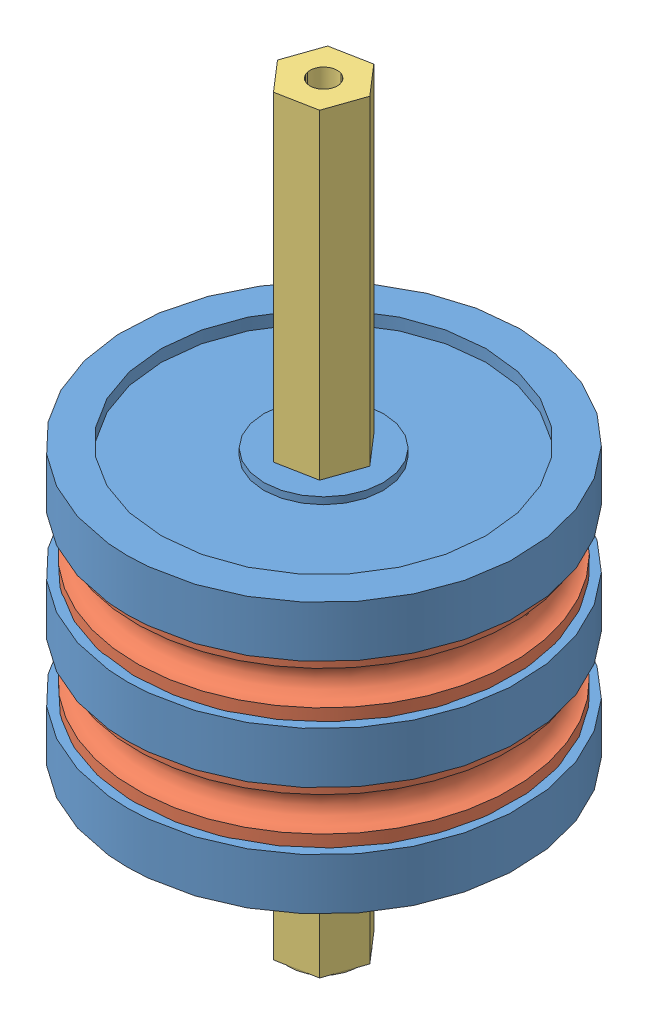
SolidWorks assembly Wheel_Assem, configuration Default. Lengths in mm.
Overall size (100.46 139.95 100.46).
6 component instances, 3 part files, 14 mates.
Components (placement in the parent):
- Wheel-1: Wheel [Default] at origin size (73.03 9.53 73.03)
- Hex_Spacer-1: Hex_Spacer [Default] at (0 8.5725 0) x (0.982054 0 -0.188601) z (0.188601 0 0.982054) size (71.22 12.7 71.22)
- Wheel-2: Wheel [Default] at (0 20.32 0) size (73.03 9.53 73.03)
- Hex_Spacer-2: Hex_Spacer [Default] at (0 28.8925 0) x (0.65436 0 0.756183) z (-0.756183 0 0.65436) size (71.22 12.7 71.22)
- Wheel-3: Wheel [Default] at (0 40.64 0) size (73.03 9.53 73.03)
- Hex_Shaft-1: Hex_Shaft [Default] at (0 -30.9284 0) x (0.982054 0 -0.188601) z (0.188601 0 0.982054) size (14.66 139.95 12.7)
Mates (geometry in assembly coordinates):
- Concentric1: concentric aligned: circle of Wheel-1; circle of Hex_Spacer-1
- Coincident1: coincident anti-aligned: plane of Wheel-1 through (0 8.5725 0) normal (0 1 0); plane of Hex_Spacer-1 through (0 8.5725 0) normal (0 -1 0)
- Parallel1: parallel aligned: plane of Wheel-1 through (2.4028 2.2225 -6.9275) normal (0.188601 0 0.982054); plane of Hex_Spacer-1 through (2.571 21.2725 -7.4124) normal (0.188601 0 0.982054)
- Coincident3: coincident anti-aligned: plane of Hex_Spacer-1 through (0 21.2725 0) normal (0 1 0); plane of Wheel-2 through (0 21.2725 0) normal (0 -1 0)
- Coincident5: coincident aligned: plane of Wheel-1 through (7.2008 2.2225 -1.3829) normal (-0.756183 0 0.65436); plane of Wheel-2 through (7.2008 22.5425 -1.3829) normal (-0.756183 0 0.65436)
- Coincident6: coincident anti-aligned: plane of Wheel-2 through (0 28.8925 0) normal (0 1 0); plane of Hex_Spacer-2 through (0 28.8925 0) normal (0 -1 0)
- Concentric3: concentric aligned: circle of Wheel-2; circle of Hex_Spacer-2
- Parallel2: parallel aligned: plane of Wheel-1 through (-4.798 2.2225 -5.5446) normal (0.944784 0 0.327694); plane of Hex_Spacer-2 through (-5.1339 41.5925 -5.9327) normal (0.944784 0 0.327694)
- Concentric4: concentric aligned: circle of Wheel-1; circle of Wheel-2
- Coincident8: coincident anti-aligned: plane of Hex_Spacer-2 through (0 41.5925 0) normal (0 1 0); plane of Wheel-3 through (0 41.5925 0) normal (0 -1 0)
- Concentric5: concentric aligned: circle of Wheel-1; circle of Wheel-3
- Coincident9: coincident aligned: plane of Wheel-1 through (-4.798 2.2225 -5.5446) normal (0.944784 0 0.327694); plane of Wheel-3 through (-4.798 42.8625 -5.5446) normal (0.944784 0 0.327694)
- Concentric6: concentric anti-aligned: circle of Wheel-3; circle of Hex_Shaft-1
- Coincident10: coincident: line of Wheel-3 through (7.2008 49.2125 -1.3829) axis (-0.327694 0 0.944784); plane of Hex_Shaft-1 through (4.798 108.7716 5.5446) normal (0.944784 0 0.327694)
